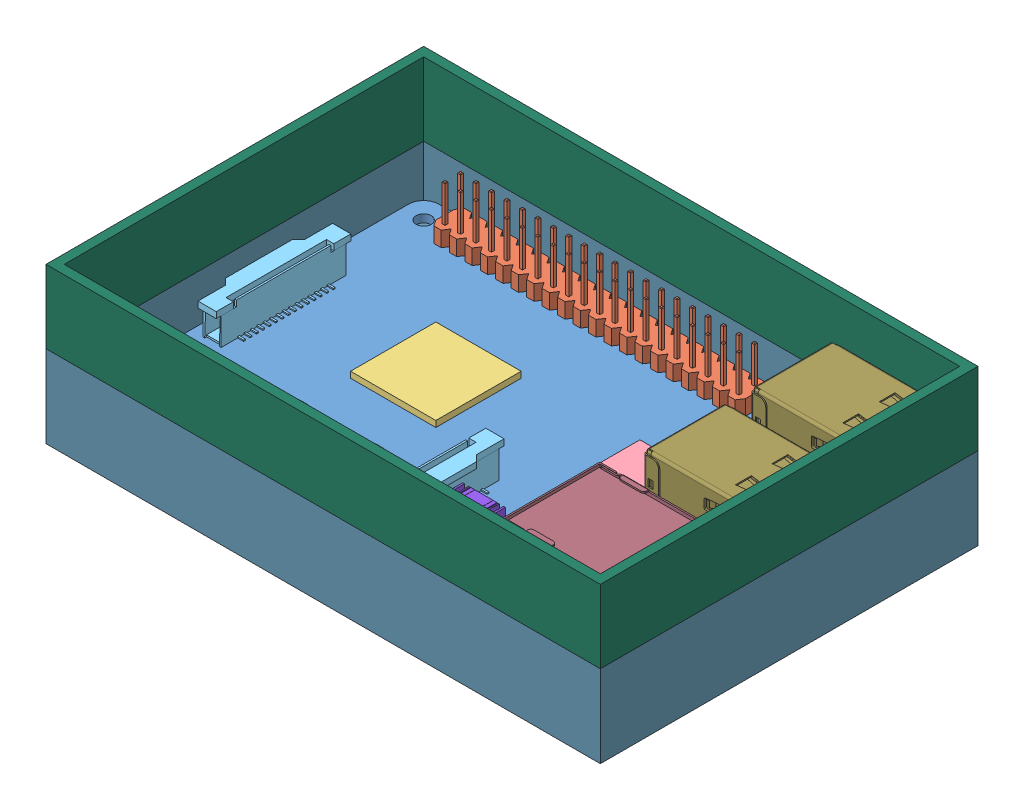
SolidWorks assembly Assem3, configuration Default. Lengths in mm.
Overall size (92.42 27.92 69.27).
23 component instances, 20 part files, 28 mates.
Components (placement in the parent):
- mefile-1: mefile [Default] at origin size (91.42 27.08 66.27)
  - Mainboard2_1-1: Mainboard2_1 [Default] at origin size (85 1.3 56)
  - GPIO_1-1: GPIO_1 [Default] at (-11.37 0 -24.5) x (0 0 1) z (-1 0 0) size (5 11.5 50.8)
  - Processor_1-1: Processor_1 [Default] at (-15.5 0 -3) x (0 0 1) z (-1 0 0) size (14 1 14)
  - GPU_1-1: GPU_1 [Default] at (15.25 0 -5.75) x (0 0 1) z (-1 0 0) size (9.1 1 9.1)
  - CameraAssembly_1-1: CameraAssembly_1 [Default] at (10.0885 -2.9159 16.55) x (-1 0 0) z (0 0 -1) size (6.09 6.17 23.84)
  - CameraAssembly_1-2: CameraAssembly_1 [Default] at (-46.3885 -2.9159 0) size (6.09 6.17 23.84)
  - HDMI_1-1: HDMI_1 [Default] at (-10.2 0.27 29.3) size (15 8.38 12.15)
  - RAM_1-1: RAM_1 [Default] at (0.5 -2.3 -6) x (0 0 1) z (-1 0 0) size (12 1 12)
  - Audio_1-1: Audio_1 [Default] at (10.9 0.15 21.75) size (7 6 14.8)
  - MicroSDSocket_1-1: MicroSDSocket_1 [Default] at (-34.5 -1.3 -0.7) x (0 0 -1) z (-1 0 0) size (13 1.3 14)
  - MicroSD_1-1: MicroSD_1 [Default] at (-37 -2.3 0.1) x (0 0 1) z (-1 0 0) size (11.29 1 15)
  - micro USB2_1-1: micro USB2_1 [Default] at (-17.2704 -5.0969 44.9026) size (22.78 22.78 22.78)
  - usb double_1-1: usb double_1 [Default] at (30.38 -0.09 -18.85) x (0 0 -1) z (1 0 0) size (15.6 18.75 17.92)
  - usb double_1-2: usb double_1 [Default] at (30.38 -0.09 -1.25) x (0 0 -1) z (1 0 0) size (15.6 18.75 17.92)
  - RJ45-LED_1-1: RJ45-LED_1 [Default] at (34.11 7.4 17.348) x (1 0 0) z (0 -1 0) size (23.41 18.34 17.45)
- Part4^Assem3-1: Part4^Assem3 [Default] at (0 -1.3 0) x (-1 0 0) z (0 -1 0) (virtual)
- Part5^Assem3-1: Part5^Assem3 [Default] at (0 -1.3 0) x (-1 0 0) z (0 -1 0) (virtual)
- Part6^Assem3-1: Part6^Assem3 [Default] at (0 -1.3 0) x (-1 0 0) z (0 -1 0) (virtual)
- Part7^Assem3-1: Part7^Assem3 [Default] at (0 -1.3 0) x (-1 0 0) z (0 -1 0) (virtual)
- Part8^Assem3-1: Part8^Assem3 [Default] at (0 -1.3 0) x (-1 0 0) z (0 -1 0) (virtual)
- Part9^Assem3-1: Part9^Assem3 [Default] at (0 -1.3 0) x (-1 0 0) z (0 -1 0) size (91 62 13.5) (virtual)
- Part11^Assem3-1: Part11^Assem3 [Default] at (0 6.2 0) x (1 0 0) z (0 1 0) size (91 62 12) (virtual)
Mates (geometry in assembly coordinates):
- InPlace2: in place: plane of mefile-1/Mainboard2_1-1 through (40 -1.3 25.5) normal (0 -1 0); plane of ? through (0 -1.3 0) normal (0 -1 0); moOrthogonalPlaneRef_w of mefile-1/Mainboard2_1-1 through (40 -1.3 25.5) normal (0 -1 0); unknown of ?; plane of mefile-1/Mainboard2_1-1 through (40 -1.3 25.5) normal (0 -1 0); line of ? through (-55 0 -1.3) axis (0 -1 0); plane of mefile-1/Mainboard2_1-1 through (40 -1.3 25.5) normal (0 -1 0); unknown of ?
- Coincident4: coincident aligned: plane of mefile-1/Mainboard2_1-1; plane of Part4^Assem3-1
- Coincident5: coincident aligned: moOrthogonalPlaneRef_w of mefile-1/Mainboard2_1-1 through (0 -1.3 0) normal (0 0 -1); plane of Part4^Assem3-1
- Coincident6: coincident anti-aligned: moOrthogonalPlaneRef_w of mefile-1/Mainboard2_1-1 through (0 -1.3 0) normal (1 0 0); plane of Part4^Assem3-1
- InPlace3: in place: plane of mefile-1/Mainboard2_1-1 through (40 -1.3 25.5) normal (0 -1 0); plane of ? through (0 -1.3 0) normal (0 -1 0); plane of mefile-1/Mainboard2_1-1 through (40 -1.3 25.5) normal (0 -1 0); unknown of ?; plane of mefile-1/Mainboard2_1-1 through (40 -1.3 25.5) normal (0 -1 0); line of ? through (-55 0 -1.3) axis (0 -1 0); plane of mefile-1/Mainboard2_1-1 through (40 -1.3 25.5) normal (0 -1 0); unknown of ?
- Coincident7: coincident aligned: plane of mefile-1/Mainboard2_1-1; plane of Part5^Assem3-1
- Coincident8: coincident aligned: moOrthogonalPlaneRef_w of mefile-1/Mainboard2_1-1 through (0 -1.3 0) normal (0 0 -1); plane of Part5^Assem3-1
- Coincident9: coincident anti-aligned: moOrthogonalPlaneRef_w of mefile-1/Mainboard2_1-1 through (0 -1.3 0) normal (1 0 0); plane of Part5^Assem3-1
- InPlace4: in place: plane of mefile-1/Mainboard2_1-1 through (40 -1.3 25.5) normal (0 -1 0); plane of ? through (0 -1.3 0) normal (0 -1 0); plane of mefile-1/Mainboard2_1-1 through (40 -1.3 25.5) normal (0 -1 0); unknown of ?; plane of mefile-1/Mainboard2_1-1 through (40 -1.3 25.5) normal (0 -1 0); line of ? through (-55 0 -1.3) axis (0 -1 0); plane of mefile-1/Mainboard2_1-1 through (40 -1.3 25.5) normal (0 -1 0); unknown of ?
- Coincident10: coincident aligned: plane of mefile-1/Mainboard2_1-1; plane of Part6^Assem3-1
- Coincident11: coincident aligned: moOrthogonalPlaneRef_w of mefile-1/Mainboard2_1-1 through (0 -1.3 0) normal (0 0 -1); plane of Part6^Assem3-1
- Coincident12: coincident anti-aligned: moOrthogonalPlaneRef_w of mefile-1/Mainboard2_1-1 through (0 -1.3 0) normal (1 0 0); plane of Part6^Assem3-1
- InPlace5: in place: plane of mefile-1/Mainboard2_1-1 through (40 -1.3 25.5) normal (0 -1 0); plane of ? through (0 -1.3 0) normal (0 -1 0); plane of mefile-1/Mainboard2_1-1 through (40 -1.3 25.5) normal (0 -1 0); unknown of ?; plane of mefile-1/Mainboard2_1-1 through (40 -1.3 25.5) normal (0 -1 0); line of ? through (-55 0 -1.3) axis (0 -1 0); plane of mefile-1/Mainboard2_1-1 through (40 -1.3 25.5) normal (0 -1 0); unknown of ?
- Coincident13: coincident aligned: plane of mefile-1/Mainboard2_1-1; plane of Part7^Assem3-1
- Coincident14: coincident aligned: moOrthogonalPlaneRef_w of mefile-1/Mainboard2_1-1 through (0 -1.3 0) normal (0 0 -1); plane of Part7^Assem3-1
- Coincident15: coincident anti-aligned: moOrthogonalPlaneRef_w of mefile-1/Mainboard2_1-1 through (0 -1.3 0) normal (1 0 0); plane of Part7^Assem3-1
- InPlace6: in place: plane of mefile-1/Mainboard2_1-1 through (40 -1.3 25.5) normal (0 -1 0); plane of ? through (0 -1.3 0) normal (0 -1 0); plane of mefile-1/Mainboard2_1-1 through (40 -1.3 25.5) normal (0 -1 0); unknown of ?; plane of mefile-1/Mainboard2_1-1 through (40 -1.3 25.5) normal (0 -1 0); line of ? through (-55 0 -1.3) axis (0 -1 0); plane of mefile-1/Mainboard2_1-1 through (40 -1.3 25.5) normal (0 -1 0); unknown of ?
- Coincident16: coincident aligned: plane of mefile-1/Mainboard2_1-1; plane of Part8^Assem3-1
- Coincident17: coincident aligned: moOrthogonalPlaneRef_w of mefile-1/Mainboard2_1-1 through (0 -1.3 0) normal (0 0 -1); plane of Part8^Assem3-1
- Coincident18: coincident anti-aligned: moOrthogonalPlaneRef_w of mefile-1/Mainboard2_1-1 through (0 -1.3 0) normal (1 0 0); plane of Part8^Assem3-1
- InPlace7: in place: plane of mefile-1/Mainboard2_1-1 through (40 -1.3 25.5) normal (0 -1 0); plane of ? through (0 -1.3 0) normal (0 -1 0); plane of mefile-1/Mainboard2_1-1 through (40 -1.3 25.5) normal (0 -1 0); unknown of ?; plane of mefile-1/Mainboard2_1-1 through (40 -1.3 25.5) normal (0 -1 0); line of ? through (-55 0 -1.3) axis (0 -1 0); plane of mefile-1/Mainboard2_1-1 through (40 -1.3 25.5) normal (0 -1 0); unknown of ?
- Coincident19: coincident aligned: plane of mefile-1/Mainboard2_1-1; plane of Part9^Assem3-1
- Coincident20: coincident aligned: moOrthogonalPlaneRef_w of mefile-1/Mainboard2_1-1 through (0 -1.3 0) normal (0 0 -1); plane of Part9^Assem3-1
- Coincident21: coincident anti-aligned: moOrthogonalPlaneRef_w of mefile-1/Mainboard2_1-1 through (0 -1.3 0) normal (1 0 0); plane of Part9^Assem3-1
- InPlace8: in place: plane of ? through (0 6.2 0) normal (0 1 0); plane of Part11^Assem3-1 through (0 6.2 0) normal (0 1 0); plane of ? through (0 6.2 0) normal (0 1 0); plane of Part11^Assem3-1 through (0 6.2 0) normal (0 0 -1); plane of ? through (0 6.2 0) normal (0 1 0); line of Part11^Assem3-1 through (-55 0 6.2) axis (0 1 0); plane of ? through (0 6.2 0) normal (0 1 0); unknown of Part11^Assem3-1
- Coincident22: coincident aligned: plane of Part9^Assem3-1; plane of Part11^Assem3-1
- Coincident23: coincident aligned: moOrthogonalPlaneRef_w of Part9^Assem3-1 through (0 6.2 0) normal (0 0 -1); plane of Part11^Assem3-1 through (0 6.2 0) normal (0 0 -1)
- Coincident24: coincident anti-aligned: moOrthogonalPlaneRef_w of Part9^Assem3-1 through (0 6.2 0) normal (-1 0 0); plane of Part11^Assem3-1
